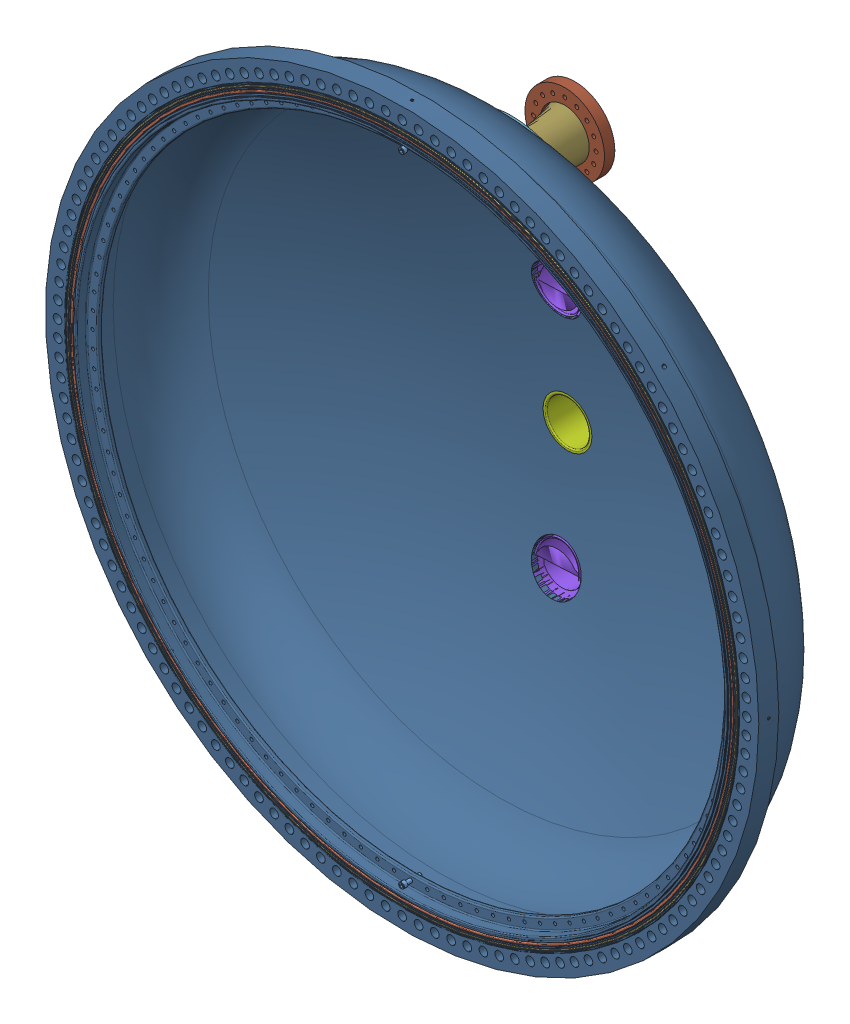
SolidWorks assembly tracking_head_assem_jordi, configuration Predeterminado. Lengths in mm.
Overall size (1480 1510.05 550.83).
22 component instances, 14 part files, 0 mates.
Components (placement in the parent):
- Hexagon_Socket_Head_Cap_Screw_5_16-18x1_255_ANSI_B18.3-1: Hexagon_Socket_Head_Cap_Screw_5_16-18x1_255_ANSI_B18.3 [Predeterminado] at (0 -660 -681.9) x (1 0 0) z (0 0 -1) size (11.91 11.91 39.8)
- Hexagon_Socket_Head_Cap_Screw_5_16-18x1_255_ANSI_B18.3-2: Hexagon_Socket_Head_Cap_Screw_5_16-18x1_255_ANSI_B18.3 [Predeterminado] at (0 660 -681.5) x (-1 0 0) z (0 0 -1) size (11.91 11.91 39.8)
- O-ring_press.1.1-1: O-ring_press.1.1 [Predeterminado] at (0 0 61.9) x (-1 0 0) z (0 0 -1) size (1377.4 1377.4 3.81)
- O-ring_H2o-1: O-ring_H2o [Predeterminado] at (0 0 61.5) x (-1 0 0) z (0 0 -1) size (1392 1392 2.61)
- head_weldment.1-1: head_weldment.1 [Predeterminado] at (0 0 -17.4) x (-1 0 0) z (0 0 -1) size (1480 1510.05 550.83)
  - reinforcement.axial.1.1.1-1: reinforcement.axial.1.1.1 [Predeterminado] at (0 -13.7355 -284.0742) x (1 0 0) z (0 0.183956 -0.982934) size (203.29 202.99 30.7)
  - nozzle_aux_l.2-1: nozzle_aux_l.2 [Predeterminado] at (0 0 -282.8) x (1 0 0) z (0 0 -1) size (165 165 21.44)
    - flange_aux_2-1: flange_aux_2 [Predeterminado] at (0 0 -69.4114) x (-1 0 0) z (0 0 -1) size (165 165 21.44)
  - nozzle_axial-1: nozzle_axial [Predeterminado] at (0 0 -282.8) x (-1 0 0) z (0 0 -1) size (165 165 85.73)
    - flange_1-1: flange_1 [Predeterminado] at (0 250 -79.4114) x (1 0 0) z (0 0 -1) size (165 165 21.44)
    - tube-1: tube [Predeterminado] at (0 0 -242.4894) size (101.6 101.6 74.63)
  - nozzle_aux_l-1: nozzle_aux_l [Predeterminado] at (0 0 -282.8) x (-1 0 0) z (0 0 -1) size (440 939.85 440)
    - nozzle_auxiliary.1-1: nozzle_auxiliary.1 [Predeterminado] at (0 -250 -242.8779) x (-1 0 0) z (0 0 1) size (440 440 440)
    - nozzle_auxiliary.1-2: nozzle_auxiliary.1 [Predeterminado] at (0 250 -242.8779) size (440 440 440)
    - flange_aux_1-1: flange_aux_1 [Predeterminado] at (0 0 -69.4114) x (-1 0 0) z (0 0 -1) size (165 165 21.44)
  - head_O_ring-1: head_O_ring [Predeterminado] at (0 0 -17.4) x (-1 0 0) z (0 0 -1) size (1480 1480 359.44)
  - nozzle_hv-1: nozzle_hv [Predeterminado] at (0 272.0886 -282.8) x (-1 0 0) z (0 0 -1) size (496.82 496.82 496.82)
    - flange_aux-1: flange_aux [Predeterminado] at (0 0 -9.4114) x (-1 0 0) z (0 0 -1) size (165 165 21.44)
    - nozzle_auxiliary-1: nozzle_auxiliary [Predeterminado] at (0 250 217.1221) size (496.82 496.82 496.82)
  - reinforcement.axial-1: reinforcement.axial [Predeterminado] at (0 0 -282.8) x (-1 0 0) z (0 0 -1) size (203.28 203.96 19.57)
  - reinforcement.axial.1.1.1-2: reinforcement.axial.1.1.1 [Predeterminado] at (0 13.7355 -284.0742) x (-1 0 0) z (0 -0.183956 -0.982934) size (203.29 202.99 30.7)
  - reinforcement.axial.1.2-1: reinforcement.axial.1.2 [Predeterminado] at (0 28.6873 -288.5308) x (-1 0 0) z (0 -0.384203 -0.923249) size (193.14 205.75 36.46)
